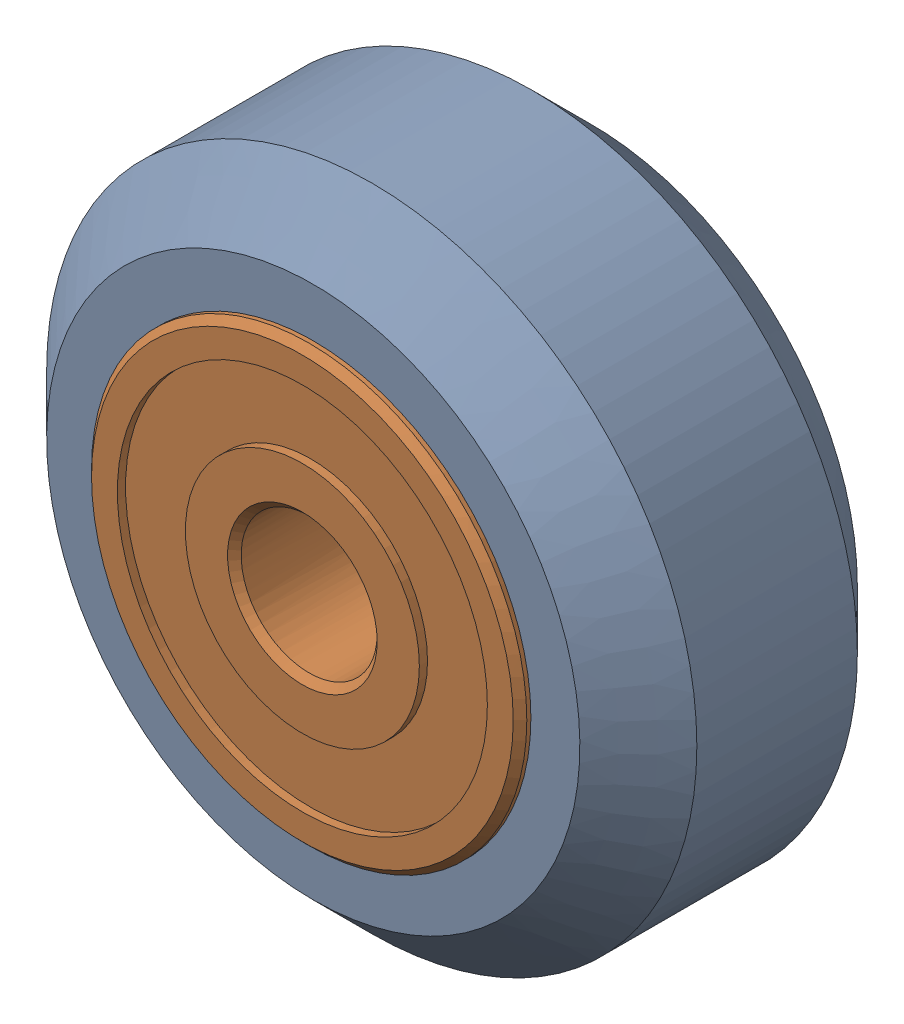
SolidWorks assembly Xtreme Solid V Wheel Assembly_4, configuration Default. Lengths in mm.
Overall size (23.9 23.9 11).
3 component instances, 2 part files, 0 mates.
Components (placement in the parent):
- Xtreme Solid V Wheel-1: Xtreme Solid V Wheel [Default] at (-84.85 -25.79 30) x (0 0 1) z (-1 0 0) size (10.2 23.9 23.9)
- Wheel+Kit+-+5x16x5mm+Sealed+Radial+Ball+Bearing.step.f3d-1: Wheel+Kit+-+5x16x5mm+Sealed+Radial+Ball+Bearing.step.f3d [Default] at (-84.85 -25.79 30) x (0 1 0) z (-1 0 0) size (16 5 16)
- Wheel+Kit+-+5x16x5mm+Sealed+Radial+Ball+Bearing.step.f3d-2: Wheel+Kit+-+5x16x5mm+Sealed+Radial+Ball+Bearing.step.f3d [Default] at (-84.85 -25.79 30) x (0 1 0) z (1 0 0) size (16 5 16)
